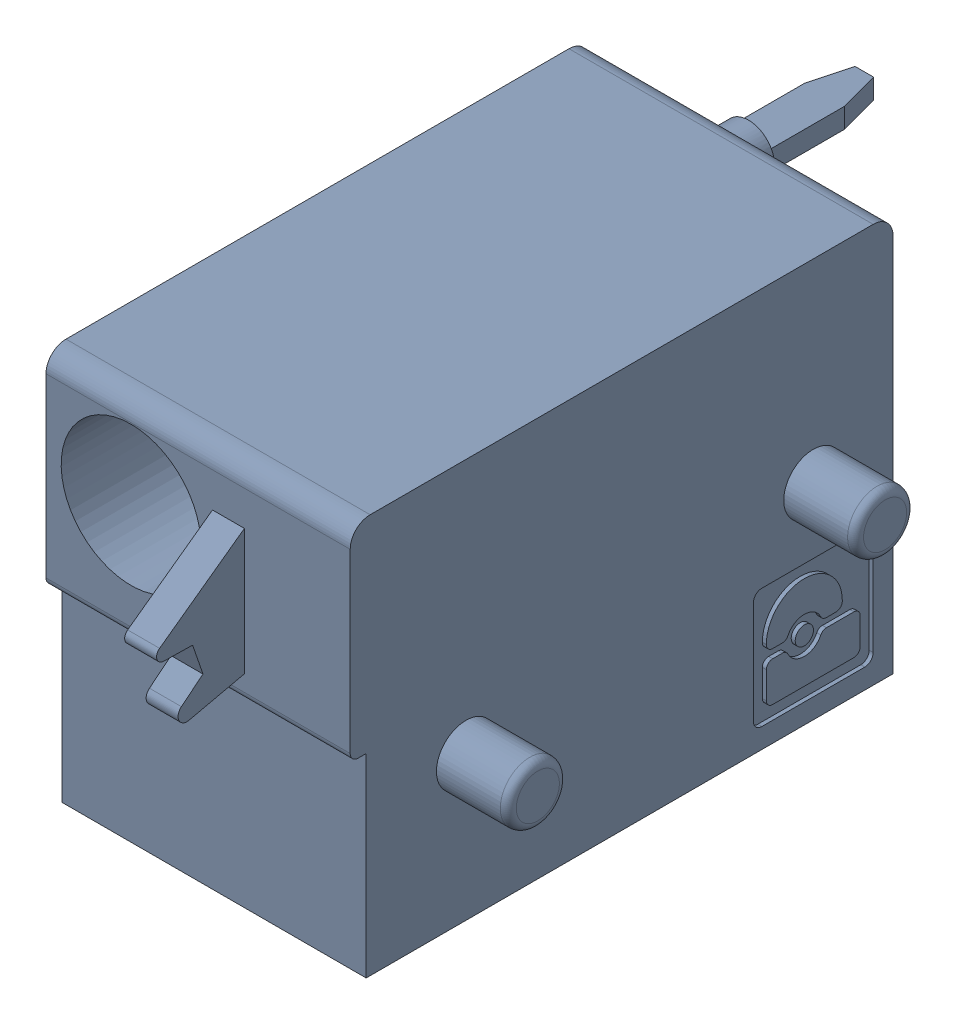
SolidWorks assembly J73, configuration Default. Lengths in mm.
Overall size (9.42 10 19.2).
2 component instances, 1 part files, 0 mates.
Components (placement in the parent):
- 1790377-1: 1790377 [Default] at (217.8051 -7.6199 0) x (0 1 0) z (1 0 0) size (10 19.2 9.42)
  - ffkdsa-v2-7.62-1: ffkdsa-v2-7.62 [Default] at (-23.7414 -38.158 -5.08) x (0 -1 0) z (0 0 1) size (19.2 10 9.42)
